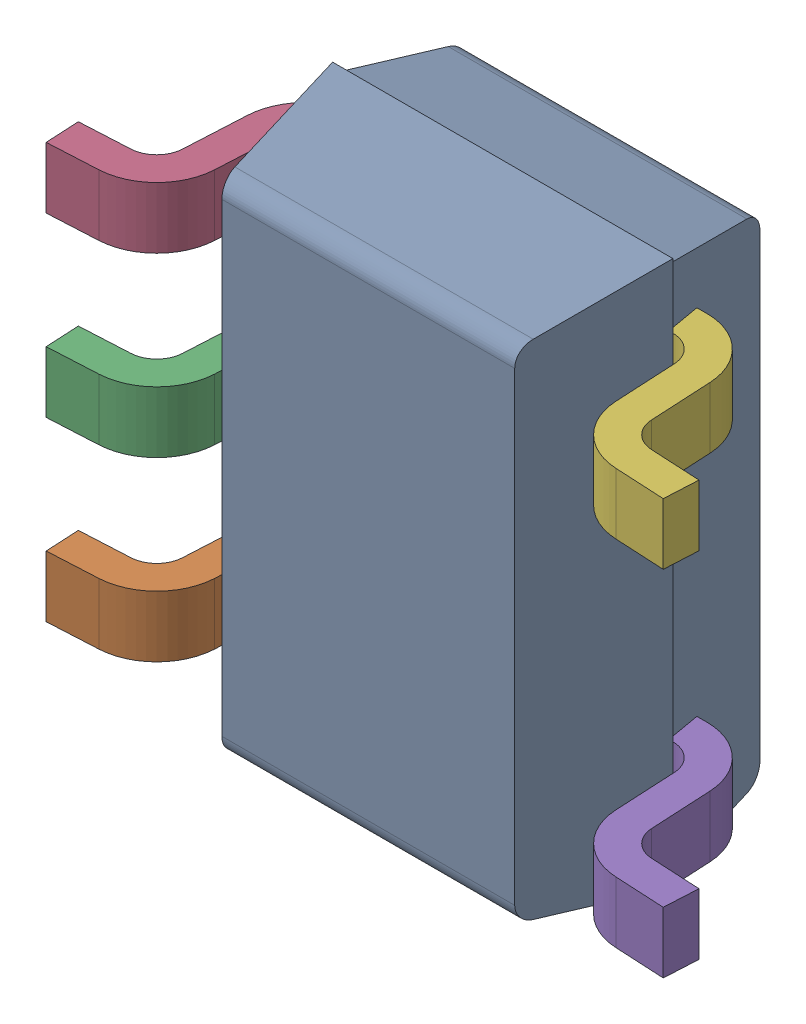
SolidWorks assembly U307_2PCB, configuration Default. Lengths in mm.
Overall size (2.28 2 0.95).
8 component instances, 6 part files, 0 mates.
Components (placement in the parent):
- DCK0005AakaMAA05A-1: DCK0005AakaMAA05A [Default] at (132.5001 89.6999 -2.1938) x (0 -1 0) z (-1 0 0) size (2 0.95 2.28)
  - BODY_MAA05-1: BODY_MAA05 [Default] at origin size (2 0.9 1.25)
  - LEADS_MAA05A-1: LEADS_MAA05A [Default] at (0.65 0 0) x (0 0 1) z (1 0 0) size (2.28 0.67 1.53)
    - LEADS_MAA05A_3-1: LEADS_MAA05A_3 [Default] at origin size (0.55 0.67 0.23)
    - LEADS_MAA05A_4-1: LEADS_MAA05A_4 [Default] at origin size (0.55 0.67 0.23)
    - LEADS_MAA05A_5-1: LEADS_MAA05A_5 [Default] at origin size (0.55 0.67 0.23)
    - LEADS_MAA05A_6-1: LEADS_MAA05A_6 [Default] at origin size (0.55 0.67 0.23)
    - LEADS_MAA05A_7-1: LEADS_MAA05A_7 [Default] at origin size (0.55 0.67 0.23)
